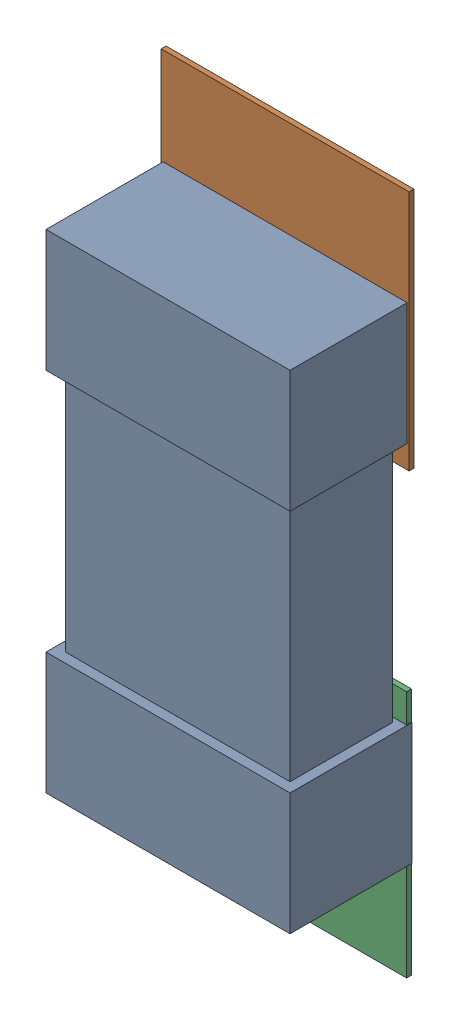
SolidWorks assembly L10, configuration Défaut. Lengths in mm.
Overall size (0.51 1.4 0.25).
5 component instances, 3 part files, 0 mates.
Components (placement in the parent):
- User Library-d0402h025-1: User Library-d0402h025 [Défaut] at (53.4162 -9.6974 0) x (0 -1 0) z (0 0 1) size (1 0.5 0.25)
- 8259735872-1: 8259735872 [Défaut] at (53.4161 -9.2465 0) size (0.51 0.5 0.01)
  - Extruded_1762-1: Extruded_1762 [Défaut] at origin size (0.51 0.5 0.01)
- 8259735712-1: 8259735712 [Défaut] at (53.4161 -10.1424 0) size (0.5 0.51 0.01)
  - Extruded_1766-1: Extruded_1766 [Défaut] at origin size (0.5 0.51 0.01)
